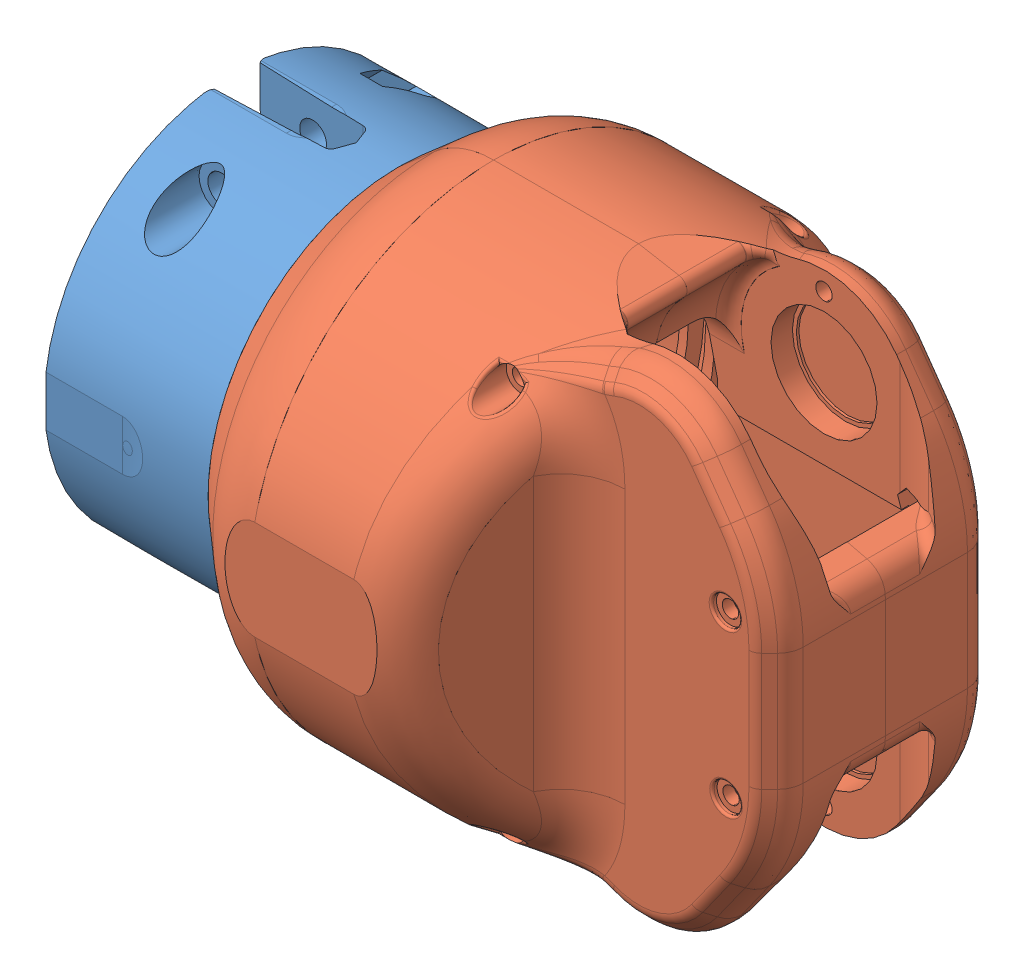
SolidWorks assembly Assem4, configuration Default. Lengths in mm.
Overall size (211.15 141.15 107.71).
3 component instances, 2 part files, 6 mates.
Components (placement in the parent):
- coupler_V6Flange-1: coupler_V6Flange [Default] at (40.3956 86.8529 151.6016) size (211.15 141.15 97.24)
- HandShellv8-1: HandShellv8 [Default] at (59.1408 86.8529 151.6016) x (0 1 0) z (0 0 -1) size (96.93 99.59 48.46)
- HandShellv8-2: HandShellv8 [Default] at (59.1408 86.8529 151.6016) x (0 -1 0) z (0 0 1) size (96.93 99.59 48.46)
Mates (geometry in assembly coordinates):
- Coincident1: coincident: plane of coupler_V6Flange-1 through (39.8876 86.8529 151.6016) normal (1 0 0); plane of HandShellv8-2 through (39.8876 49.0577 151.6016) normal (-1 0 0)
- Coincident2: coincident: circle of coupler_V6Flange-1; circle of HandShellv8-2
- Parallel1: parallel aligned: plane of coupler_V6Flange-1 through (7.3756 81.7729 189.0666) normal (0 0 1); plane of HandShellv8-2 through (59.1408 86.8529 199.0498) normal (0 0 1)
- Coincident4: coincident: plane of coupler_V6Flange-1 through (39.8876 86.8529 151.6016) normal (1 0 0); plane of HandShellv8-1 through (39.8876 124.6481 151.6016) normal (-1 0 0)
- Concentric1: concentric: circle of coupler_V6Flange-1; circle of HandShellv8-1
- Parallel2: parallel aligned: plane of coupler_V6Flange-1 through (7.3756 81.7729 114.1366) normal (0 0 -1); plane of HandShellv8-1 through (59.1408 86.8529 104.1534) normal (0 0 -1)
